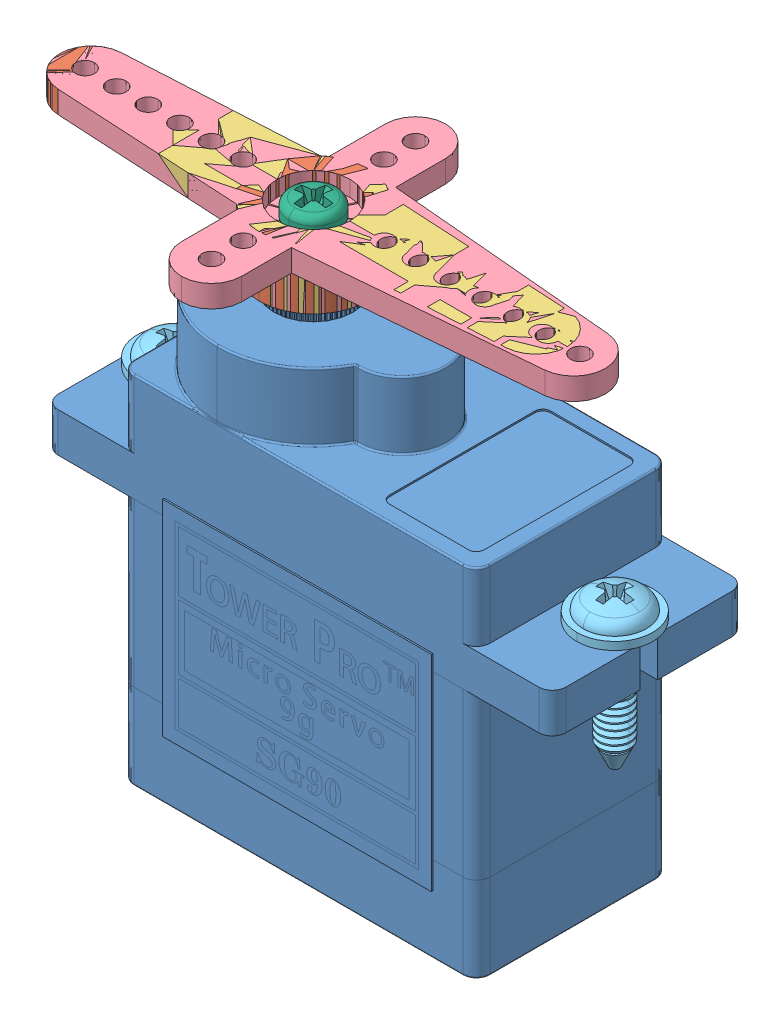
SolidWorks assembly SG90 - Micro Servo 9g - Tower Pro, configuration Varsayılan. Lengths in mm.
Overall size (37.5 32.03 16.7).
8 component instances, 6 part files, 0 mates.
Components (placement in the parent):
- SG90 - Micro Servo 9g - Tower Pro.STEP-1: SG90 - Micro Servo 9g - Tower Pro.STEP [Varsayılan] at origin size (37.5 32.03 16.7)
  - SG90 - Micro Servo 9g - Tower Pro.1_Pe_a.STEP-1: SG90 - Micro Servo 9g - Tower Pro.1_Pe_a.STEP [Varsayılan] at (6.6733 16.8178 27.7832) size (32.1 29.95 12.4)
  - SG90 - Micro Servo 9g - Tower Pro.2_Pe_a.STEP-1: SG90 - Micro Servo 9g - Tower Pro.2_Pe_a.STEP [Varsayılan] at (1.5233 37.9178 27.7832) size (19.5 3.8 6.9)
  - SG90 - Micro Servo 9g - Tower Pro.3_Pe_a.STEP-1: SG90 - Micro Servo 9g - Tower Pro.3_Pe_a.STEP [Varsayılan] at (1.5233 37.9178 27.7832) size (32.1 3.8 6.9)
  - SG90 - Micro Servo 9g - Tower Pro.4_Pe_a.STEP-1: SG90 - Micro Servo 9g - Tower Pro.4_Pe_a.STEP [Varsayılan] at (1.5233 37.9178 27.7832) size (34.5 3.8 16.7)
  - SG90 - Micro Servo 9g - Tower Pro.5_BS EN ISO 7045 - M2 x 8 - Z - 8S.STEP-1: SG90 - Micro Servo 9g - Tower Pro.5_BS EN ISO 7045 - M2 x 8 - Z - 8S.STEP [Varsayılan] at (20.5733 26.0678 27.7832) x (0 -1 0) z (0 0 1) size (9.57 4.8 4.8)
  - SG90 - Micro Servo 9g - Tower Pro.5_BS EN ISO 7045 - M2 x 8 - Z - 8S.STEP-2: SG90 - Micro Servo 9g - Tower Pro.5_BS EN ISO 7045 - M2 x 8 - Z - 8S.STEP [Varsayılan] at (-7.2267 26.0678 27.7832) x (0 -1 0) z (0 0 -1) size (9.57 4.8 4.8)
  - SG90 - Micro Servo 9g - Tower Pro.6_BS EN ISO 7045 - M2 x 4 - Z - 4S.STEP-1: SG90 - Micro Servo 9g - Tower Pro.6_BS EN ISO 7045 - M2 x 4 - Z - 4S.STEP [Varsayılan] at (1.5233 38.2178 27.7832) x (0 -1 0) z (0 0 1) size (5.28 3.1 3.1)
